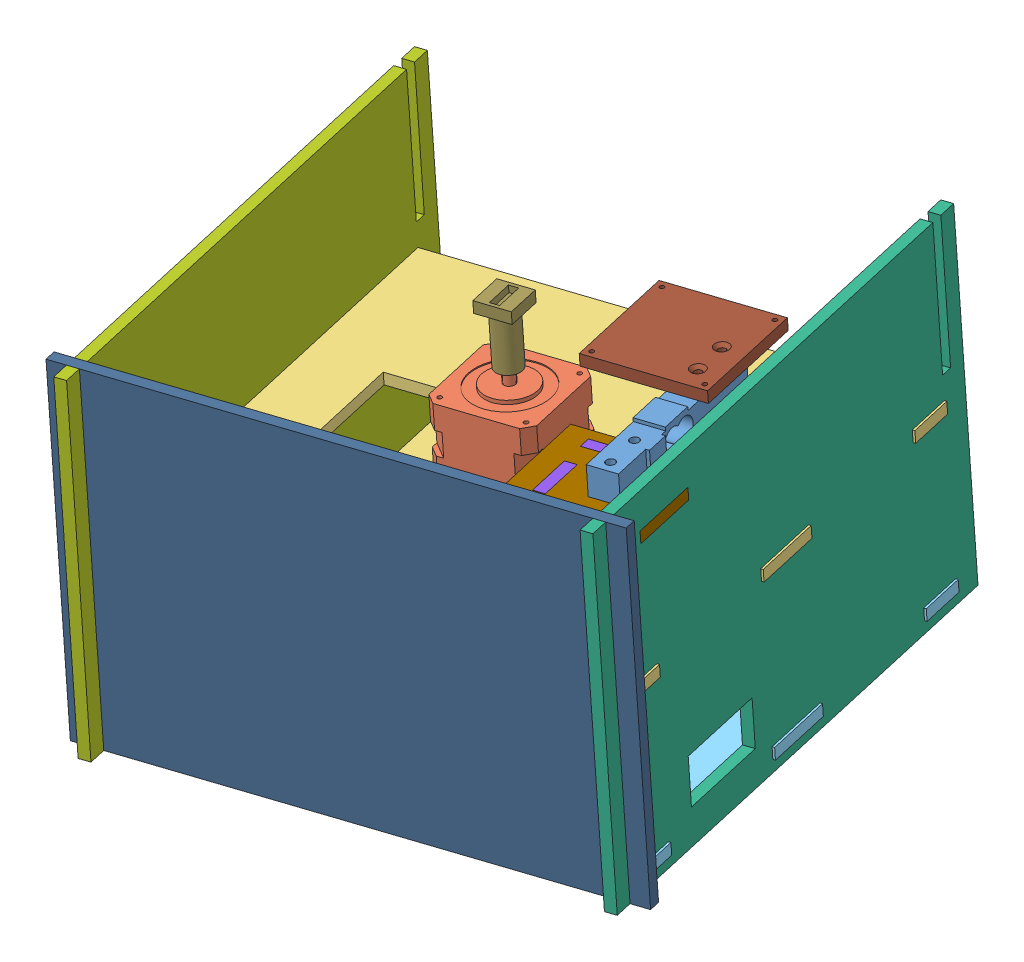
SolidWorks assembly Assembly, configuration Défaut. Lengths in mm.
Overall size (271.86 237.23 269.33).
15 component instances, 14 part files, 44 mates.
Components (placement in the parent):
- weight sensor-1: weight sensor [Défaut] at (-182.5267 -143.9588 -34.012) x (-0.971168 -0.06918 0.228136) z (-0.228015 -0.009745 -0.973609) size (14.1 14.1 80.2)
- Stepper 33-1: Stepper 33 [Défaut] at (-284.3799 -205.8651 -86.5719) x (-0.971168 -0.06918 0.228136) z (-0.069577 0.997557 0.00631) size (42 42 56)
- middle face-1: middle face [Défaut] at (-364.5223 -212.2237 34.9714) x (-0.228015 -0.009745 -0.973609) z (0.069577 -0.997557 -0.00631) size (200 212 5)
- Arduino-1: Arduino [Défaut] at (-289.4118 -266.8675 -6.8255) x (-0.228015 -0.009745 -0.973609) z (0.069577 -0.997557 -0.00631) size (84.9 100.5 10)
- bottom face-1: bottom face [Défaut] at (-199.3671 -269.3354 -208.5569) x (0.228015 0.009745 0.973609) z (0.069577 -0.997557 -0.00631) size (200 212 5)
- lateral face - hole-1: lateral face - hole [Défaut] at (-176.841 -278.4057 -111.0309) x (0.228015 0.009745 0.973609) z (-0.971168 -0.06918 0.228136) size (226 220 5)
- lateral face-1: lateral face [Défaut] at (-380.7864 -292.9335 -63.1224) x (-0.228015 -0.009745 -0.973609) z (0.971168 0.06918 -0.228136) size (226 220 5)
- back support weight sensor-1: back support weight sensor [Défaut] at (-248.7546 -199.6515 -48.7575) x (0.971168 0.06918 -0.228136) z (0.228015 0.009745 0.973609) size (30 60 5)
- back support weight sensor-2: back support weight sensor [Défaut] at (-200.483 -196.6587 10.3657) x (-0.228015 -0.009745 -0.973609) z (0.971168 0.06918 -0.228136) size (30 60 5)
- support weight sensor-1: support weight sensor [Défaut] at (-166.5048 -147.8951 -27.4538) x (0.971168 0.06918 -0.228136) z (-0.069577 0.997557 0.00631) size (55 60 5)
- back face-1: back face [Défaut] at (-365.7543 -292.5125 36.0635) x (0.971168 0.06918 -0.228136) z (0.228015 0.009745 0.973609) size (226 150 5)
- support plateau-1: support plateau [Défaut] at (-240.4989 -135.0555 -83.9552) x (0.228015 0.009745 0.973609) z (-0.069577 0.997557 0.00631) size (50 50 5)
- front face-1: front face [Défaut] at (-199.6425 -279.3802 -208.3918) x (-0.971168 -0.06918 0.228136) z (-0.228015 -0.009745 -0.973609) size (226 150 5) (hidden)
- top face-1: top face [Défaut] at (-143.1764 -123.8156 4.6393) x (-0.228015 -0.009745 -0.973609) z (-0.069577 0.997557 0.00631) size (250 250 5) (hidden)
- magnet support-1: magnet support [Défaut] at (-287.163 -165.9628 -86.3194) x (0.971168 0.06918 -0.228136) z (-0.069577 0.997557 0.00631) size (15 15 28)
Mates (geometry in assembly coordinates):
- Coïncidente1: coincident anti-aligned: plane of bottom face-1 through (-199.3671 -269.3354 -208.5569) normal (-0.069577 0.997557 0.00631); plane of lateral face-1 through (-373.2061 -282.4659 -49.5959) normal (0.069577 -0.997557 -0.00631)
- Coïncidente2: coincident anti-aligned: plane of bottom face-1 through (-372.8582 -287.4537 -49.6274) normal (-0.971168 -0.06918 0.228136); plane of lateral face-1 through (-375.9306 -292.5876 -64.2631) normal (0.971168 0.06918 -0.228136)
- Coïncidente3: coincident anti-aligned: plane of bottom face-1 through (-359.304 -287.0405 34.4981) normal (0.228015 0.009745 0.973609); plane of lateral face-1 through (-353.8248 -281.6376 33.1609) normal (-0.228015 -0.009745 -0.973609)
- Coïncidente4: coincident anti-aligned: plane of bottom face-1 through (-200.2859 -274.5434 -187.7474) normal (0.971168 0.06918 -0.228136); plane of lateral face - hole-1 through (-181.6969 -278.7516 -109.8903) normal (-0.971168 -0.06918 0.228136)
- Coïncidente6: coincident anti-aligned: plane of bottom face-1 through (-199.3671 -269.3354 -208.5569) normal (-0.069577 0.997557 0.00631); plane of lateral face - hole-1 through (-185.8129 -268.9222 -124.4313) normal (0.069577 -0.997557 -0.00631)
- Coïncidente7: coincident anti-aligned: plane of bottom face-1 through (-199.0192 -274.3232 -208.5884) normal (-0.228015 -0.009745 -0.973609); plane of lateral face - hole-1 through (-205.1941 -269.7505 -207.1881) normal (0.228015 0.009745 0.973609)
- Coïncidente8: coincident anti-aligned: plane of Arduino-1 through (-288.716 -276.843 -6.8886) normal (0.069577 -0.997557 -0.00631); plane of bottom face-1 through (-199.3671 -269.3354 -208.5569) normal (-0.069577 0.997557 0.00631)
- Coaxiale8: concentric anti-aligned: cylinder of Arduino-1 through (-287.7465 -266.7105 -13.277) axis (0.069577 -0.997557 -0.00631) radius 1; cylinder of bottom face-1 through (-286.7028 -281.6739 -13.3716) axis (-0.069577 0.997557 0.00631) radius 1
- Coaxiale9: concentric anti-aligned: cylinder of Arduino-1 through (-212.9531 -260.9071 -106.0355) axis (0.069577 -0.997557 -0.00631) radius 1; cylinder of bottom face-1 through (-211.9094 -275.8704 -106.1302) axis (-0.069577 0.997557 0.00631) radius 1
- Coïncidente9: coincident anti-aligned: plane of middle face-1 through (-364.1744 -217.2115 34.9399) normal (0.069577 -0.997557 -0.00631); plane of lateral face-1 through (-377.7286 -217.6247 -49.1857) normal (-0.069577 0.997557 0.00631)
- Coïncidente10: coincident anti-aligned: plane of middle face-1 through (-384.5691 -217.917 -78.394) normal (-0.971168 -0.06918 0.228136); plane of lateral face-1 through (-375.9306 -292.5876 -64.2631) normal (0.971168 0.06918 -0.228136)
- Coïncidente11: coincident anti-aligned: plane of middle face-1 through (-362.9077 -216.9913 14.0989) normal (-0.228015 -0.009745 -0.973609); plane of lateral face-1 through (-363.2555 -212.0035 14.1304) normal (0.228015 0.009745 0.973609)
- Coïncidente12: coincident anti-aligned: plane of Stepper 33-1 through (-284.3799 -205.8651 -86.5719) normal (0.069577 -0.997557 -0.00631); plane of middle face-1 through (-364.5223 -212.2237 34.9714) normal (-0.069577 0.997557 0.00631)
- Distance1: distance = 79 mm aligned: plane of Stepper 33-1 through (-296.8323 -194.9587 -62.1955) normal (0.228015 0.009745 0.973609); plane of middle face-1 through (-364.1744 -217.2115 34.9399) normal (0.228015 0.009745 0.973609)
- Distance2: distance = 79 mm anti-aligned: plane of Stepper 33-1 through (-309.4558 -195.6116 -98.1599) normal (-0.971168 -0.06918 0.228136); plane of lateral face-1 through (-375.9306 -292.5876 -64.2631) normal (0.971168 0.06918 -0.228136)
- Coïncidente15: coincident anti-aligned: plane of middle face-1 through (-364.5223 -212.2237 34.9714) normal (-0.069577 0.997557 0.00631); plane of back support weight sensor-1 through (-214.709 -201.2271 -51.5796) normal (0.069577 -0.997557 -0.00631)
- Coïncidente16: coincident anti-aligned: plane of middle face-1 through (-196.0779 -204.88 -61.0419) normal (0.228015 0.009745 0.973609); plane of back support weight sensor-1 through (-248.7546 -199.6515 -48.7575) normal (-0.228015 -0.009745 -0.973609)
- Coïncidente17: coincident anti-aligned: plane of middle face-1 through (-214.3612 -206.2148 -51.6111) normal (0.971168 0.06918 -0.228136); plane of back support weight sensor-1 through (-218.1879 -151.3492 -51.264) normal (-0.971168 -0.06918 0.228136)
- Coïncidente18: coincident anti-aligned: plane of middle face-1 through (-207.5207 -205.9225 -22.4028) normal (0.971168 0.06918 -0.228136); plane of back support weight sensor-2 through (-200.483 -196.6587 10.3657) normal (-0.971168 -0.06918 0.228136)
- Coïncidente19: coincident anti-aligned: plane of middle face-1 through (-207.5207 -205.9225 -22.4028) normal (-0.228015 -0.009745 -0.973609); plane of back support weight sensor-2 through (-206.4916 -150.711 -23.1964) normal (0.228015 0.009745 0.973609)
- Coïncidente21: coincident anti-aligned: plane of middle face-1 through (-364.5223 -212.2237 34.9714) normal (-0.069577 0.997557 0.00631); plane of back support weight sensor-2 through (-203.0127 -200.5888 -23.512) normal (0.069577 -0.997557 -0.00631)
- Coïncidente23: coincident anti-aligned: plane of back support weight sensor-1 through (-223.0437 -151.6951 -50.1234) normal (-0.069577 0.997557 0.00631); plane of support weight sensor-1 through (-166.5048 -147.8951 -27.4538) normal (0.069577 -0.997557 -0.00631)
- Coïncidente24: coincident anti-aligned: plane of back support weight sensor-1 through (-247.6145 -199.6028 -43.8895) normal (0.228015 0.009745 0.973609); plane of support weight sensor-1 through (-218.5358 -146.3614 -51.2325) normal (-0.228015 -0.009745 -0.973609)
- Coïncidente25: coincident anti-aligned: plane of back support weight sensor-2 through (-195.6271 -196.3128 9.2251) normal (0.971168 0.06918 -0.228136); plane of support weight sensor-1 through (-211.3998 -145.9181 -42.6371) normal (-0.971168 -0.06918 0.228136)
- Coïncidente27: coincident anti-aligned: plane of weight sensor-1 through (-200.8135 -144.7403 -112.0955) normal (0.069577 -0.997557 -0.00631); plane of support weight sensor-1 through (-166.8527 -142.9073 -27.4223) normal (-0.069577 0.997557 0.00631)
- Coaxiale12: concentric anti-aligned: cylinder of weight sensor-1 through (-193.1165 -144.5832 -52.0678) axis (-0.069577 0.997557 0.00631) radius 2; cylinder of support weight sensor-1 through (-193.1165 -144.5832 -52.0678) axis (0.069577 -0.997557 -0.00631) radius 2
- Coaxiale13: concentric anti-aligned: cylinder of weight sensor-1 through (-189.6963 -144.4371 -37.4637) axis (-0.069577 0.997557 0.00631) radius 2; cylinder of support weight sensor-1 through (-189.6963 -144.4371 -37.4637) axis (0.069577 -0.997557 -0.00631) radius 2
- Coïncidente29: coincident anti-aligned: plane of lateral face-1 through (-358.2509 -201.7843 38.5338) normal (-0.228015 -0.009745 -0.973609); plane of back face-1 through (-364.6142 -292.4638 40.9316) normal (0.228015 0.009745 0.973609)
- Coïncidente30: coincident aligned: plane of lateral face-1 through (-363.5657 -141.9797 34.0443) normal (-0.069577 0.997557 0.00631); plane of back face-1 through (-375.0508 -142.8303 41.8782) normal (-0.069577 0.997557 0.00631)
- Coïncidente31: coincident anti-aligned: plane of lateral face-1 through (-375.9306 -292.5876 -64.2631) normal (0.971168 0.06918 -0.228136); plane of back face-1 through (-351.989 -291.5644 37.9658) normal (-0.971168 -0.06918 0.228136)
- Coïncidente32: coincident anti-aligned: plane of weight sensor-1 through (-201.6902 -132.1711 -112.0159) normal (-0.069577 0.997557 0.00631); plane of support plateau-1 through (-240.4989 -135.0555 -83.9552) normal (0.069577 -0.997557 -0.00631)
- Coïncidente33: coincident anti-aligned: plane of weight sensor-1 through (-201.6902 -132.1711 -112.0159) normal (-0.069577 0.997557 0.00631); plane of support plateau-1 through (-240.4989 -135.0555 -83.9552) normal (0.069577 -0.997557 -0.00631)
- Coaxiale18: concentric aligned: circle of weight sensor-1; circle of support plateau-1
- Coaxiale19: concentric aligned: circle of weight sensor-1; circle of support plateau-1
- Coïncidente34: coincident anti-aligned: plane of middle face-1 through (-203.8896 -204.4942 -208.1467) normal (-0.228015 -0.009745 -0.973609); plane of front face-1 through (-199.6425 -279.3802 -208.3918) normal (0.228015 0.009745 0.973609)
- Coïncidente35: coincident anti-aligned: plane of lateral face - hole-1 through (-176.841 -278.4057 -111.0309) normal (0.971168 0.06918 -0.228136); plane of front face-1 through (-200.7826 -279.4289 -213.2599) normal (-0.971168 -0.06918 0.228136)
- Coïncidente36: coincident aligned: plane of lateral face - hole-1 through (-214.9349 -130.0926 -206.3046) normal (-0.069577 0.997557 0.00631); plane of front face-1 through (-422.9339 -144.8766 -162.5797) normal (-0.069577 0.997557 0.00631)
- Coaxiale20: concentric aligned: circle of support plateau-1; circle of top face-1
- Coïncidente42: coincident anti-aligned: plane of support plateau-1 through (-240.8468 -130.0677 -83.9237) normal (-0.069577 0.997557 0.00631); plane of top face-1 through (-143.1764 -123.8156 4.6393) normal (0.069577 -0.997557 -0.00631)
- Coaxiale21: concentric anti-aligned: cylinder of support plateau-1 through (-195.113 -126.8655 -85.8775) axis (0.069577 -0.997557 -0.00631) radius 1; circle of top face-1
- Coïncidente44: coincident anti-aligned: circle of support plateau-1; cylinder of top face-1 through (-248.2249 -125.3504 -118.6468) axis (0.069577 -0.997557 -0.00631) radius 1
- Coïncidente45: coincident anti-aligned: plane of Stepper 33-1 through (-288.7633 -166.0866 -84.4028) normal (-0.971168 -0.06918 0.228136); plane of magnet support-1 through (-291.0476 -143.172 -87.1784) normal (0.971168 0.06918 -0.228136)
- Coaxiale22: concentric aligned: cylinder of Stepper 33-1 through (-288.2762 -150.0019 -86.2185) axis (0.069577 -0.997557 -0.00631) radius 2.5; cylinder of magnet support-1 through (-288.7633 -143.019 -86.1743) axis (0.069577 -0.997557 -0.00631) radius 2.5
- Coïncidente48: coincident anti-aligned: plane of Stepper 33-1 through (-287.163 -165.9628 -86.3194) normal (-0.069577 0.997557 0.00631); plane of magnet support-1 through (-287.163 -165.9628 -86.3194) normal (0.069577 -0.997557 -0.00631)
